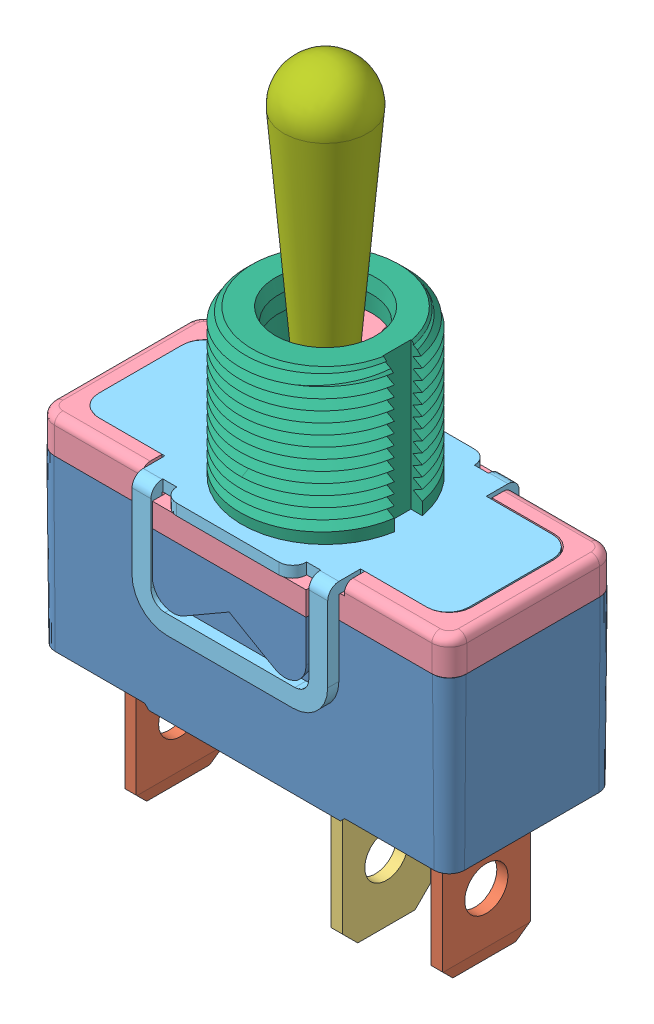
SolidWorks assembly 638H_SLASH_2 - SWITCH, TOGGLE, ON-OFF-(ON), STD BAT, configuration Default. Lengths in mm.
Overall size (29.5 51.71 14.05).
8 component instances, 7 part files, 4 mates.
Components (placement in the parent):
- 63-348-1: 63-348 [Default] at origin
- 64-899-1: 64-899 [Default] at (10.55 2.3 -0.05) x (-1 0 0) z (0 0 -1)
- 64-899-2: 64-899 [Default] at (-10.55 2.3 -0.05)
- 264-34-0-1: 264-34-0 [Default] at (4.3 -10.73 0.05) x (0 0 1) z (-1 0 0)
- 63-94-1: 63-94 [Default] at (0 12.5 0)
- 63-267-1: 63-267 [Default] at (-0.05 15 0.05)
- 63-97-1: 63-97 [Default] at (-0.05 15 0.05)
- 63-65-1: 63-65 [Default] at (-0.05 18.9811 0.05)
Mates (geometry in assembly coordinates):
- Angle1: planar angle = 1.27409 rad aligned: plane of 63-65-1 through (-0.05 18.9811 0.05) normal (1 0 0); plane of 63-267-1 through (-0.05 15 0.05) normal (0 1 0)
- Concentric2: concentric aligned: cylinder of 63-94-1 through (0 19.8 8.4) axis (0 0 1) radius 1.025; cylinder of 63-65-1 through (-0.05 18.9811 -3.95) axis (0 0 1) radius 1
- Width1: width aligned: plane of 63-94-1 through (-4.6259 23.2 2.375) normal (0 0 -1); plane of 63-65-1 through (4.6259 23.2 -2.375) normal (0 0 1); plane of 63-94-1 through (-0.05 6.9811 -2.2) normal (0 0 -1); plane of 63-65-1 through (-0.05 6.9811 2.3) normal (0 0 1)
- Concentric3: concentric aligned: circle of 63-97-1; cone of 63-65-1 through (-0.05 37.7233 0.05) axis (0 -1 0)
